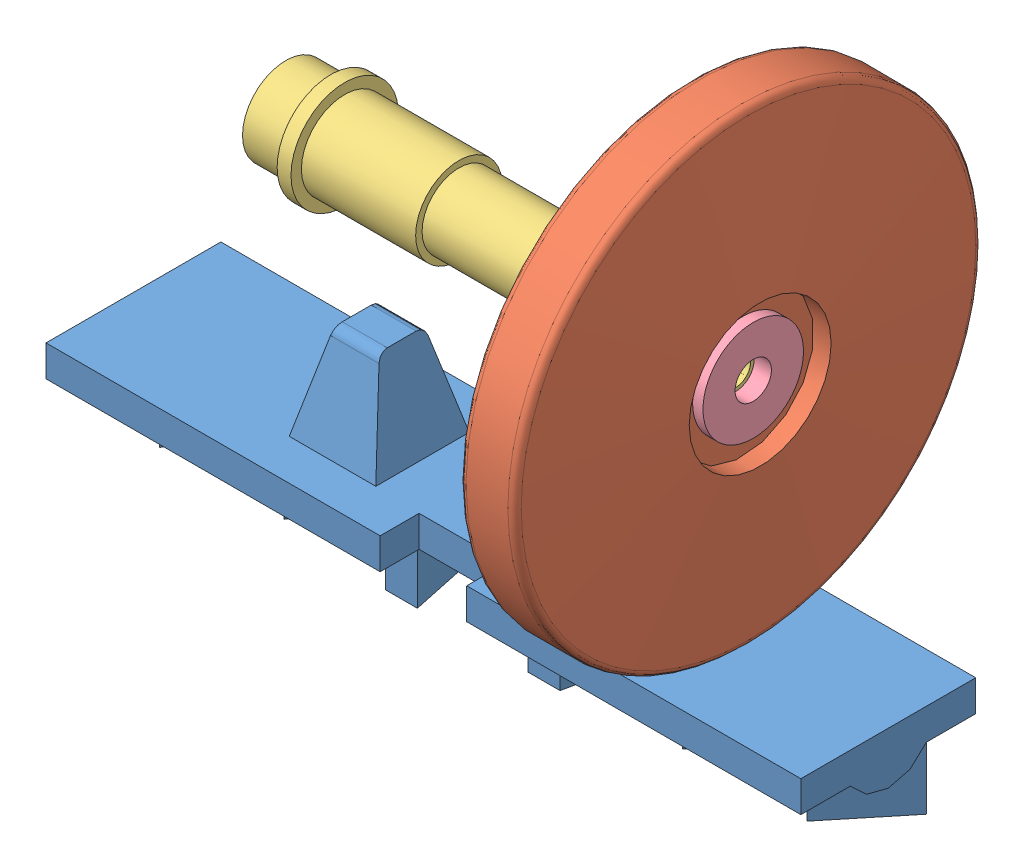
SolidWorks assembly Схема оси, configuration 00. Lengths in mm.
Overall size (218.02 162 135).
4 component instances, 4 part files, 12 mates.
Components (placement in the parent):
- Трак гусеницы-1: Трак гусеницы [По умолчанию] at (0 -9 0) x (1 0 0) z (0 0 -1) size (218.02 54 50.5)
- Каток 135 (205)-1: Каток 135 (205) [--] at (60.5717 67.5 0) size (24.5 135 135)
- Ось под 205-1: Ось под 205 [--] at (0 67.5 0) size (130 31 31)
- Крышка оси-1: Крышка оси [--] at (65 67.5 0) size (5 29 29)
Mates (geometry in assembly coordinates):
- Совпадение2: coincident: plane of Трак гусеницы-1 through (0 -9 0) normal (-1 0 0); plane of assembly through (0 0 0) normal (1 0 0)
- Совпадение3: coincident: plane of Трак гусеницы-1 through (109 0 -25.25) normal (0 1 0); plane of assembly through (0 0 0) normal (0 1 0)
- Совпадение4: coincident: plane of Трак гусеницы-1 through (0 -9 0) normal (0 0 1); plane of assembly through (0 0 0) normal (0 0 1)
- Касательность1: tangent: plane of Трак гусеницы-1 through (109 0 -25.25) normal (0 1 0); cylinder of Каток 135 (205)-1 through (-582.761 67.5 0) axis (-1 0 0) radius 67.5
- Совпадение5: coincident: plane of Каток 135 (205)-1 through (60.5717 67.5 0) normal (0 0 1); plane of assembly through (0 0 0) normal (0 0 1)
- Расстояние1: distance = 2 mm: line of Трак гусеницы-1 through (50.5 0 13.5) axis (0 0 -1); plane of Каток 135 (205)-1 through (52.5 97.5 0) normal (-1 0 0)
- Совпадение7: coincident: plane of Ось под 205-1 through (0 67.5 0) normal (0 0 1); plane of assembly through (0 0 0) normal (0 0 1)
- Совпадение8: coincident: plane of Ось под 205-1 through (0 67.5 0) normal (1 0 0); plane of assembly through (0 0 0) normal (1 0 0)
- Совпадение9: coincident: plane of Каток 135 (205)-1 through (60.5717 67.5 0) normal (0 1 0); plane of Ось под 205-1 through (0 67.5 0) normal (0 1 0)
- Совпадение10: coincident: plane of Ось под 205-1 through (0 67.5 0) normal (0 0 1); plane of Крышка оси-1 through (65 67.5 0) normal (0 0 1)
- Совпадение11: coincident: plane of Ось под 205-1 through (0 67.5 0) normal (0 1 0); plane of Крышка оси-1 through (65 67.5 0) normal (0 1 0)
- Совпадение12: coincident: plane of Ось под 205-1 through (65 80 0) normal (1 0 0); plane of Крышка оси-1 through (65 67.5 0) normal (1 0 0)
